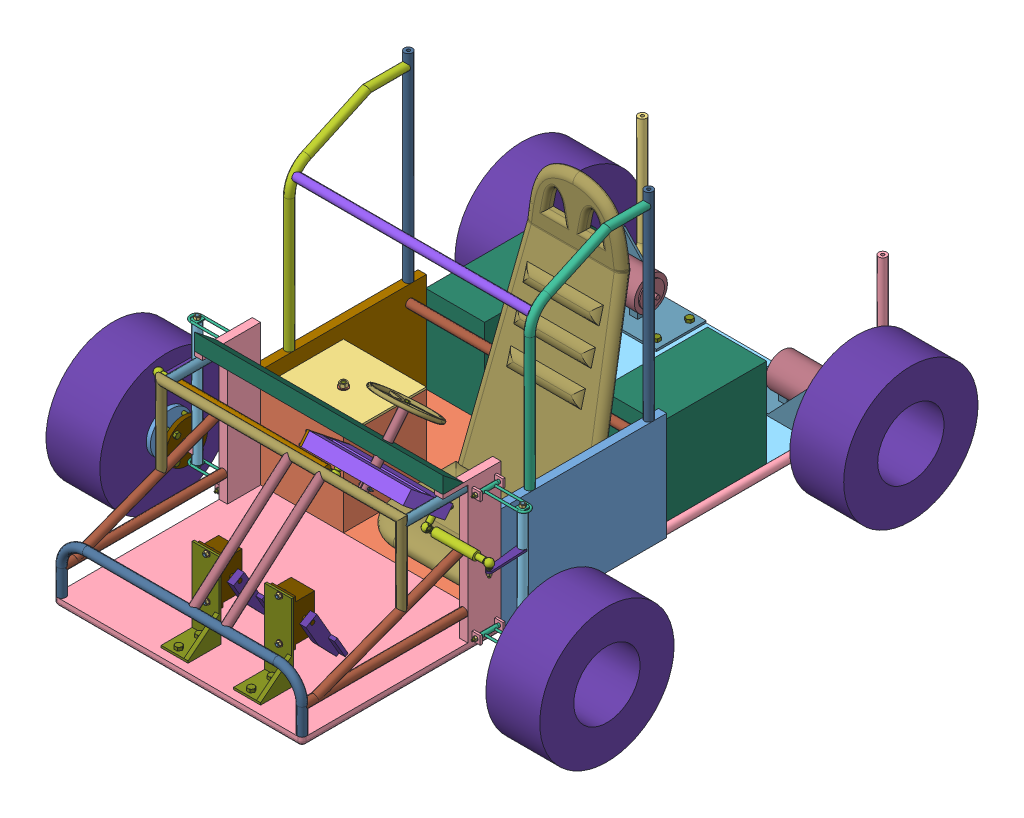
SolidWorks assembly FA2, configuration Default. Lengths in mm.
Overall size (1513.16 1181.12 1856.74).
253 component instances, 57 part files, 73 mates.
Components (placement in the parent):
- MC (1)-1: MC (1) [Default] at (-134.0082 207.4417 1496.2137) size (1191.26 1083.62 1343.85)
  - SPL-1: SPL [Default] at (646.5449 178.7927 -996.551) size (25.4 330.2 508)
  - BP-1: BP [Default] at (111.0665 -124.6065 -917.4807) size (711.2 25.4 508)
  - BBR-2: BBR [Default] at (-77.3551 -47.0728 -1647.3326) x (-1 0 0) z (0 -1 0) size (25.4 687.13 407.73)
  - BBL-1: BBL [Default] at (659.2449 -47.0728 -1647.3326) x (-1 0 0) z (0 -1 0) size (25.4 687.13 407.73)
  - BC-1: BC [Default] at (357.2961 -116.9228 -1647.3326) x (-1 0 0) z (0 0 -1) size (723.9 12.7 609.6)
  - FTL-1: FTL [Default] at (659.245 611.9935 -719.4116) x (0 -0.899323 -0.437285) z (-1 0 -0.000001) size (433.75 589.6 27.41)
  - FTR-1: FTR [Default] at (-77.355 611.9935 -719.4116) x (0 -0.899323 -0.437285) z (-1 0 -0.000001) size (433.75 589.6 27.38)
  - TC-1: TC [Default] at (652.8949 660.2535 -644.2461) x (0 -0.542655 -0.839955) z (-1 0 -0.000001) size (25.4 25.4 723.9)
  - SPR-1: SPR [Default] at (-90.0551 178.7927 -996.551) size (25.4 330.2 508)
  - BT-1: BT [Default] at (-77.3551 205.5935 -995.2506) x (0.000001 0 -1) z (1 0 0.000001) size (25.4 609.6 25.4)
  - BT-2: BT [Default] at (659.2449 205.5935 -995.2506) x (0.000001 0 -1) z (1 0 0.000001) size (25.4 609.6 25.4)
  - FB-1: FB [Default] at (-71.0051 154.7935 -986.9326) x (1 0 0) z (0 0.990518 0.137381) size (723.9 25.4 25.4)
  - seat-1: seat [Default] at (418.0013 -99.2065 -848.8249) size (437.03 835.23 478.09)
  - EA1-1: EA1 [Default] at (125.7912 -160.5315 -1631.3403) x (0 0 1) z (-1 0 0) size (411.48 411.48 1349.16)
    - EB1-1: EB1 [Default] at (60.2077 126.1588 196.7963) size (101.6 101.6 238.25)
    - EP1-1: EP1 [Default] at (60.2077 56.3088 69.7963) x (0 0 1) z (-1 0 0) size (254 133.35 152.4)
    - EA2-1: EA2 [Default] at (45.9187 58.6487 138.5565) size (411.48 411.48 213.36)
      - EP2-1: EP2 [Default] at (14.289 67.5101 114.1198) size (127 127 48.26)
      - hex bolt_ai-1: hex bolt_ai [HBOLT 0.4375-20x1.375x1.125-N] at (-36.511 67.5101 106.0934) x (0 0 1) z (-0.866025 -0.5 0) size (42.95 18.33 15.88)
      - hex bolt_ai-2: hex bolt_ai [HBOLT 0.4375-20x1.375x1.125-N] at (14.289 118.3101 106.0934) x (0 0 1) z (0 -1 0) size (42.95 18.33 15.88)
      - hex bolt_ai-3: hex bolt_ai [HBOLT 0.4375-20x1.375x1.125-N] at (14.289 16.7101 106.0934) x (0 0 1) z (-0.866025 0.5 0) size (42.95 18.33 15.88)
      - hex bolt_ai-4: hex bolt_ai [HBOLT 0.4375-20x1.375x1.125-N] at (65.089 67.5101 106.0934) x (0 0 1) z (-0.866025 0.5 0) size (42.95 18.33 15.88)
      - EB2-1: EB2 [Default] at (14.289 67.5101 129.9948) x (-1 0 0) z (0 0 -1) size (411.48 411.48 165.1)
      - flat washer type a wide_ai-1: flat washer type a wide_ai [Preferred Wide FW 0.4375] at (-36.511 67.5101 132.103) x (0 0 1) z (-0.923728 -0.383049 0) size (2.11 31.75 31.75)
      - flat washer type a wide_ai-2: flat washer type a wide_ai [Preferred Wide FW 0.4375] at (14.289 118.3101 132.103) x (0 0 1) z (1 0 0) size (2.11 31.75 31.75)
      - flat washer type a wide_ai-3: flat washer type a wide_ai [Preferred Wide FW 0.4375] at (14.289 16.7101 132.103) x (0 0 1) z (1 0 0) size (2.11 31.75 31.75)
      - flat washer type a wide_ai-4: flat washer type a wide_ai [Preferred Wide FW 0.4375] at (65.089 67.5101 132.103) x (0 0 1) z (1 0 0) size (2.11 31.75 31.75)
      - hex thick nut_ai-1: hex thick nut_ai [HTNUT 0.4375-14-D-N] at (14.289 16.7101 143.8632) x (0.055202 -0.998475 0) z (0 0 1) size (17.48 20.18 11.76)
      - hex thick nut_ai-2: hex thick nut_ai [HTNUT 0.4375-14-D-N] at (-36.511 67.5101 143.8632) x (0.547044 -0.837104 0) z (0 0 1) size (17.48 20.18 11.76)
      - hex thick nut_ai-3: hex thick nut_ai [HTNUT 0.4375-14-D-N] at (65.089 67.5101 143.8632) x (-0.982324 -0.18719 0) z (0 0 1) size (17.48 20.18 11.76)
      - hex thick nut_ai-4: hex thick nut_ai [HTNUT 0.4375-14-D-N] at (14.289 118.3101 143.8632) x (0.055202 -0.998475 0) z (0 0 1) size (17.48 20.18 11.76)
    - hex bolt_ai-8: hex bolt_ai [HBOLT 0.3125-18x1.375x0.875-N] at (17.0277 169.3388 215.4653) x (0 0 -1) z (0 1 0) size (40.89 14.66 12.7)
    - hex bolt_ai-9: hex bolt_ai [HBOLT 0.3125-18x1.375x0.875-N] at (103.3877 169.3388 215.4653) x (0 0 -1) z (0.866025 -0.5 0) size (40.89 14.66 12.7)
    - hex bolt_ai-10: hex bolt_ai [HBOLT 0.3125-18x1.375x0.875-N] at (103.3877 82.9788 215.4653) x (0 0 -1) z (0.866025 0.5 0) size (40.89 14.66 12.7)
    - hex bolt_ai-11: hex bolt_ai [HBOLT 0.3125-18x1.375x0.875-N] at (17.0277 82.9788 215.4653) x (0 0 -1) z (-0.866025 -0.5 0) size (40.89 14.66 12.7)
    - flat washer type a narrow_ai-1: flat washer type a narrow_ai [Preferred Narrow FW 0.3125] at (17.0277 169.3388 190.4463) x (0 0 1) z (-1 0 0) size (1.65 17.48 17.48)
    - flat washer type a narrow_ai-2: flat washer type a narrow_ai [Preferred Narrow FW 0.3125] at (103.3877 82.9788 190.4463) x (0 0 1) z (-1 0 0) size (1.65 17.48 17.48)
    - flat washer type a narrow_ai-3: flat washer type a narrow_ai [Preferred Narrow FW 0.3125] at (17.0277 82.9788 188.7953) x (0 0 -1) z (1 0 0) size (1.65 17.48 17.48)
    - flat washer type a narrow_ai-4: flat washer type a narrow_ai [Preferred Narrow FW 0.3125] at (103.3877 169.3388 188.7953) x (0 0 -1) z (0.923728 0.383049 0) size (1.65 17.48 17.48)
    - hex thick nut_ai-1: hex thick nut_ai [HTNUT 0.3125-18-D-N] at (103.3877 169.3388 188.7953) x (0.866025 0.5 0) z (0 0 1) size (12.7 14.66 8.53)
    - hex thick nut_ai-2: hex thick nut_ai [HTNUT 0.3125-18-D-N] at (17.0277 82.9788 180.2609) x (-0.866025 0.5 0) z (0 0 -1) size (12.7 14.66 8.53)
    - hex thick nut_ai-3: hex thick nut_ai [HTNUT 0.3125-18-D-N] at (103.3877 82.9788 181.9119) x (-0.866025 -0.5 0) z (0 0 -1) size (12.7 14.66 8.53)
    - hex thick nut_ai-4: hex thick nut_ai [HTNUT 0.3125-18-D-N] at (17.0277 169.3388 180.2609) x (-0.866025 -0.5 0) z (0 0 -1) size (12.7 14.66 8.53)
  - EA1-2: EA1 [Default] at (456.0986 -160.5315 -1510.9249) x (0 0 -1) z (1 0 0) size (411.48 411.48 1349.16)
    - EB1-1: EB1 [Default] at (60.2077 126.1588 196.7963) size (101.6 101.6 238.25)
    - EP1-1: EP1 [Default] at (60.2077 56.3088 69.7963) x (0 0 1) z (-1 0 0) size (254 133.35 152.4)
    - EA2-1: EA2 [Default] at (45.9187 58.6487 138.5565) size (411.48 411.48 213.36)
      - EP2-1: EP2 [Default] at (14.289 67.5101 114.1198) size (127 127 48.26)
      - hex bolt_ai-1: hex bolt_ai [HBOLT 0.4375-20x1.375x1.125-N] at (-36.511 67.5101 106.0934) x (0 0 1) z (-0.866025 -0.5 0) size (42.95 18.33 15.88)
      - hex bolt_ai-2: hex bolt_ai [HBOLT 0.4375-20x1.375x1.125-N] at (14.289 118.3101 106.0934) x (0 0 1) z (0 -1 0) size (42.95 18.33 15.88)
      - hex bolt_ai-3: hex bolt_ai [HBOLT 0.4375-20x1.375x1.125-N] at (14.289 16.7101 106.0934) x (0 0 1) z (-0.866025 0.5 0) size (42.95 18.33 15.88)
      - hex bolt_ai-4: hex bolt_ai [HBOLT 0.4375-20x1.375x1.125-N] at (65.089 67.5101 106.0934) x (0 0 1) z (-0.866025 0.5 0) size (42.95 18.33 15.88)
      - EB2-1: EB2 [Default] at (14.289 67.5101 129.9948) x (-1 0 0) z (0 0 -1) size (411.48 411.48 165.1)
      - flat washer type a wide_ai-1: flat washer type a wide_ai [Preferred Wide FW 0.4375] at (-36.511 67.5101 132.103) x (0 0 1) z (-0.923728 -0.383049 0) size (2.11 31.75 31.75)
      - flat washer type a wide_ai-2: flat washer type a wide_ai [Preferred Wide FW 0.4375] at (14.289 118.3101 132.103) x (0 0 1) z (1 0 0) size (2.11 31.75 31.75)
      - flat washer type a wide_ai-3: flat washer type a wide_ai [Preferred Wide FW 0.4375] at (14.289 16.7101 132.103) x (0 0 1) z (1 0 0) size (2.11 31.75 31.75)
      - flat washer type a wide_ai-4: flat washer type a wide_ai [Preferred Wide FW 0.4375] at (65.089 67.5101 132.103) x (0 0 1) z (1 0 0) size (2.11 31.75 31.75)
      - hex thick nut_ai-1: hex thick nut_ai [HTNUT 0.4375-14-D-N] at (14.289 16.7101 143.8632) x (0.055202 -0.998475 0) z (0 0 1) size (17.48 20.18 11.76)
      - hex thick nut_ai-2: hex thick nut_ai [HTNUT 0.4375-14-D-N] at (-36.511 67.5101 143.8632) x (0.547044 -0.837104 0) z (0 0 1) size (17.48 20.18 11.76)
      - hex thick nut_ai-3: hex thick nut_ai [HTNUT 0.4375-14-D-N] at (65.089 67.5101 143.8632) x (-0.982324 -0.18719 0) z (0 0 1) size (17.48 20.18 11.76)
      - hex thick nut_ai-4: hex thick nut_ai [HTNUT 0.4375-14-D-N] at (14.289 118.3101 143.8632) x (0.055202 -0.998475 0) z (0 0 1) size (17.48 20.18 11.76)
    - hex bolt_ai-8: hex bolt_ai [HBOLT 0.3125-18x1.375x0.875-N] at (17.0277 169.3388 215.4653) x (0 0 -1) z (0 1 0) size (40.89 14.66 12.7)
    - hex bolt_ai-9: hex bolt_ai [HBOLT 0.3125-18x1.375x0.875-N] at (103.3877 169.3388 215.4653) x (0 0 -1) z (0.866025 -0.5 0) size (40.89 14.66 12.7)
    - hex bolt_ai-10: hex bolt_ai [HBOLT 0.3125-18x1.375x0.875-N] at (103.3877 82.9788 215.4653) x (0 0 -1) z (0.866025 0.5 0) size (40.89 14.66 12.7)
    - hex bolt_ai-11: hex bolt_ai [HBOLT 0.3125-18x1.375x0.875-N] at (17.0277 82.9788 215.4653) x (0 0 -1) z (-0.866025 -0.5 0) size (40.89 14.66 12.7)
    - flat washer type a narrow_ai-1: flat washer type a narrow_ai [Preferred Narrow FW 0.3125] at (17.0277 169.3388 190.4463) x (0 0 1) z (-1 0 0) size (1.65 17.48 17.48)
    - flat washer type a narrow_ai-2: flat washer type a narrow_ai [Preferred Narrow FW 0.3125] at (103.3877 82.9788 190.4463) x (0 0 1) z (-1 0 0) size (1.65 17.48 17.48)
    - flat washer type a narrow_ai-3: flat washer type a narrow_ai [Preferred Narrow FW 0.3125] at (17.0277 82.9788 188.7953) x (0 0 -1) z (1 0 0) size (1.65 17.48 17.48)
    - flat washer type a narrow_ai-4: flat washer type a narrow_ai [Preferred Narrow FW 0.3125] at (103.3877 169.3388 188.7953) x (0 0 -1) z (0.923728 0.383049 0) size (1.65 17.48 17.48)
    - hex thick nut_ai-1: hex thick nut_ai [HTNUT 0.3125-18-D-N] at (103.3877 169.3388 188.7953) x (0.866025 0.5 0) z (0 0 1) size (12.7 14.66 8.53)
    - hex thick nut_ai-2: hex thick nut_ai [HTNUT 0.3125-18-D-N] at (17.0277 82.9788 180.2609) x (-0.866025 0.5 0) z (0 0 -1) size (12.7 14.66 8.53)
    - hex thick nut_ai-3: hex thick nut_ai [HTNUT 0.3125-18-D-N] at (103.3877 82.9788 181.9119) x (-0.866025 -0.5 0) z (0 0 -1) size (12.7 14.66 8.53)
    - hex thick nut_ai-4: hex thick nut_ai [HTNUT 0.3125-18-D-N] at (17.0277 169.3388 180.2609) x (-0.866025 -0.5 0) z (0 0 -1) size (12.7 14.66 8.53)
  - hex bolt_ai-1: hex bolt_ai [HBOLT 0.5000-13x1.375x1.25-N] at (157.5949 -88.6272 -1621.9326) x (0 -1 0) z (-1 0 0) size (44.17 22 19.05)
  - hex bolt_ai-2: hex bolt_ai [HBOLT 0.5000-13x1.375x1.25-N] at (157.5949 -88.6272 -1520.3326) x (0 -1 0) z (0.5 0 -0.866025) size (44.17 22 19.05)
  - hex bolt_ai-3: hex bolt_ai [HBOLT 0.5000-13x1.375x1.25-N] at (424.2949 -88.6272 -1520.3326) x (0 -1 0) z (1 0 0) size (44.17 22 19.05)
  - hex bolt_ai-4: hex bolt_ai [HBOLT 0.5000-13x1.375x1.25-N] at (602.0949 -88.6272 -1621.9326) x (0 -1 0) z (-0.5 0 -0.866025) size (44.17 22 19.05)
  - hex bolt_ai-5: hex bolt_ai [HBOLT 0.5000-13x1.375x1.25-N] at (424.2949 -88.6272 -1621.9326) x (0 -1 0) z (0.5 0 -0.866025) size (44.17 22 19.05)
  - hex bolt_ai-6: hex bolt_ai [HBOLT 0.5000-13x1.375x1.25-N] at (602.0949 -88.6272 -1520.3326) x (0 -1 0) z (-0.5 0 0.866025) size (44.17 22 19.05)
  - hex bolt_ai-7: hex bolt_ai [HBOLT 0.5000-13x1.375x1.25-N] at (-20.2051 -88.6272 -1621.9326) x (0 -1 0) z (-1 0 0) size (44.17 22 19.05)
  - hex bolt_ai-8: hex bolt_ai [HBOLT 0.5000-13x1.375x1.25-N] at (-20.2051 -88.6272 -1520.3326) x (0 -1 0) z (1 0 0) size (44.17 22 19.05)
  - flat washer type a wide_ai-1: flat washer type a wide_ai [Preferred Wide FW 0.5] at (157.5949 -119.6914 -1520.3326) x (0 -1 0) z (0.546944 0 -0.837169) size (2.77 34.92 34.92)
  - flat washer type a wide_ai-2: flat washer type a wide_ai [Preferred Wide FW 0.5] at (157.5949 -119.6914 -1621.9326) x (0 -1 0) z (0.967366 0 0.253384) size (2.77 34.92 34.92)
  - flat washer type a wide_ai-3: flat washer type a wide_ai [Preferred Wide FW 0.5] at (424.2949 -119.6914 -1621.9326) x (0 -1 0) z (-0.558017 0 -0.829829) size (2.77 34.92 34.92)
  - flat washer type a wide_ai-4: flat washer type a wide_ai [Preferred Wide FW 0.5] at (-20.2051 -119.6914 -1520.3326) x (0 -1 0) z (0.590888 0 -0.806754) size (2.77 34.92 34.92)
  - flat washer type a wide_ai-5: flat washer type a wide_ai [Preferred Wide FW 0.5] at (602.0949 -119.6914 -1520.3326) x (0 -1 0) z (0.610265 0 -0.792197) size (2.77 34.92 34.92)
  - flat washer type a wide_ai-6: flat washer type a wide_ai [Preferred Wide FW 0.5] at (424.2949 -119.6914 -1520.3326) x (0 -1 0) z (0.837672 0 -0.546174) size (2.77 34.92 34.92)
  - flat washer type a wide_ai-7: flat washer type a wide_ai [Preferred Wide FW 0.5] at (602.0949 -119.6914 -1621.9326) x (0 -1 0) z (0.97172 0 -0.236136) size (2.77 34.92 34.92)
  - flat washer type a wide_ai-8: flat washer type a wide_ai [Preferred Wide FW 0.5] at (-20.2051 -119.6914 -1621.9326) x (0 -1 0) z (0.345214 0 -0.938524) size (2.77 34.92 34.92)
  - hex nut_ai-1: hex nut_ai [HNUT 0.5000-13-D-N] at (157.5949 -131.0706 -1520.3326) x (-0.5 0 -0.866025) z (0 -1 0) size (19.05 22 11.38)
  - hex nut_ai-2: hex nut_ai [HNUT 0.5000-13-D-N] at (-20.2051 -131.0706 -1621.9326) x (-0.866025 0 -0.5) z (0 -1 0) size (19.05 22 11.38)
  - hex nut_ai-3: hex nut_ai [HNUT 0.5000-13-D-N] at (-20.2051 -131.0706 -1520.3326) x (0 0 -1) z (0 -1 0) size (19.05 22 11.38)
  - hex nut_ai-4: hex nut_ai [HNUT 0.5000-13-D-N] at (157.5949 -131.0706 -1621.9326) x (0 0 -1) z (0 -1 0) size (19.05 22 11.38)
  - hex nut_ai-5: hex nut_ai [HNUT 0.5000-13-D-N] at (424.2949 -131.0706 -1520.3326) x (0 0 1) z (0 -1 0) size (19.05 22 11.38)
  - hex nut_ai-6: hex nut_ai [HNUT 0.5000-13-D-N] at (424.2949 -131.0706 -1621.9326) x (-0.866025 0 0.5) z (0 -1 0) size (19.05 22 11.38)
  - hex nut_ai-8: hex nut_ai [HNUT 0.5000-13-D-N] at (602.0949 -131.0706 -1520.3326) x (-0.866025 0 -0.5) z (0 -1 0) size (19.05 22 11.38)
  - hex nut_ai-9: hex nut_ai [HNUT 0.5000-13-D-N] at (602.0949 -131.0706 -1621.9326) x (-0.866025 0 -0.5) z (0 -1 0) size (19.05 22 11.38)
  - hex bolt_ai-11: hex bolt_ai [HBOLT 0.5000-13x3x1.25-N] at (62.3449 -133.8521 -656.7326) x (0 1 0) z (-0.5 0 0.866025) size (85.45 22 19.05)
  - flat washer type a narrow_ai-1: flat washer type a narrow_ai [Preferred Narrow FW 0.5] at (62.3449 -99.2065 -656.7326) x (0 -1 0) z (0 0 1) size (2.41 26.97 26.97)
  - hex nut_ai-10: hex nut_ai [HNUT 0.5000-13-D-N] at (62.3449 -87.8273 -656.7326) x (1 0 0) z (0 1 0) size (19.05 22 11.38)
- FCA1-1: FCA1 [Default] at (-224.0632 159.0352 1576.0811) size (1513.16 852.83 849.49)
  - FCP1-1: FCP1 [Default] at origin size (812.8 457.2 609.6)
  - STA1-2: STA1 [Default] at (558.8 334.6162 -409.4012) x (-0.999987 0.003219 0.004024) z (0 0.780869 -0.624695) size (320.68 259.28 240.21)
    - STP10-3: STP10 [Default] at origin size (304.8 155.79 25.4)
      - spur gear_ai-4: spur gear_ai [Inch - Spur gear 6DP 25T 20PA 1FW ---S25N3.0H2.0L1.0S1] x (0 0 1) z (-0.989908 0.141715 0) size (25.4 113.98 114.2)
      - rack spur rectangular_ai-2: rack spur rectangular_ai [Inch - Rack-spur - rectangular 6DP 20PA 1FW 1.5PH 12L---SAll] at (-154.037 -91.44 25.4) size (304.8 42.33 25.4)
    - STP01-11: STP01 [Default] at (138.063 -75.0375 -39.3517) x (0 1 0) z (0 0 -1) size (23.88 20.07 47.75)
    - STP03-3: STP03 [Default] at (150.763 -97.79 31.75) x (0 0 -1) z (1 0 0) size (39.69 165.1 311.15)
    - STP04-3: STP04 [Default] at (150.763 -97.79 -7.9375) x (0 0 1) z (-1 0 0) size (39.69 165.1 6.59)
    - socket head cap screw_ai-1: socket head cap screw_ai [HX-SHCS 0.125-40x0.5x0.5-N] at (160.288 64.135 28.575) x (-1 0 0) z (0 0.866025 0.5) size (15.88 5.21 5.21)
    - socket head cap screw_ai-2: socket head cap screw_ai [HX-SHCS 0.125-40x0.5x0.5-N] at (160.288 64.135 -4.7625) x (-1 0 0) z (0 0.866025 0.5) size (15.88 5.21 5.21)
    - socket head cap screw_ai-4: socket head cap screw_ai [HX-SHCS 0.125-40x0.5x0.5-N] at (160.288 -94.615 28.575) x (-1 0 0) z (0 0.866025 0.5) size (15.88 5.21 5.21)
    - socket head cap screw_ai-7: socket head cap screw_ai [HX-SHCS 0.125-40x0.5x0.5-N] at (160.288 -94.615 -4.7625) x (-1 0 0) z (0 0.866025 0.5) size (15.88 5.21 5.21)
    - STP01-10: STP01 [Default] at (-141.337 -75.0375 -39.3517) x (0 -1 0) z (0 0 -1) size (23.88 20.07 47.75)
    - STP05-2: STP05 [Default] at (-154.037 -58.6317 0) x (1 0 0) z (0 0 -1) size (304.8 32.77 26.99)
    - STP06-1: STP06 [Default] at (-0.0036 -0.0251 180.975) x (0.5 -0.866025 0) z (0 0 1) size (189.81 189.81 12.01)
    - STP07-1: STP07 [Default] at (-0.0036 -0.0251 -33.528) x (-0.141715 -0.989908 0) z (0 0 1) size (28 24.77 211.33)
    - FWP4-1: FWP4 [Default] at (-20.7057 3.2593 -20.828) x (0 0 1) z (0.989908 -0.141715 0) size (12.7 12.7 39.95)
    - hex bolt_ai-1: hex bolt_ai [HBOLT 0.2500-20x0.75x0.75-N] at (-0.0036 -0.0251 188.9252) x (0 0 -1) z (0.5 0.866025 0) size (23.83 12.85 11.13)
  - STP08-1: STP08 [Default] at (469.9 381 -431.8) x (0 0 -1) z (1 0 0) size (63.5 50.8 762)
  - STP02-1: STP02 [Default] at (889.5958 256.5577 -445.8437) x (-0.961205 0 0.275836) z (0 1 0) size (16.51 16.51 46.05)
  - SP3-1: SP3 [Default] at (889.5958 238.8316 -445.8437) x (-0.086724 0 -0.996232) z (0 -1 0) size (120.39 25.32 6.35)
  - FWA1-1: FWA1 [Default] at (1025.989 75.5387 -589.4868) x (0 -0.682582 -0.730809) z (-1 0 0) size (411.48 411.48 257.81)
    - FWP5-2: FWP5 [Default] at (27.9791 75.0582 101.7677) size (127 127 48.26)
    - FWP1-1: FWP1 [Default] at (27.9791 75.0582 53.5077) size (127 127 48.26)
    - EB2-1: EB2 [Default] at (27.9791 75.0582 50.3327) x (-1 0 0) z (0 0 1) size (411.48 411.48 165.1)
    - internal tooth-lock washers_ai-1: internal tooth-lock washers_ai [Internal Tooth LW Type A-0.375] at (78.7791 75.0582 49.3167) x (0.992449 -0.122662 0) z (-0.122662 -0.992449 0) size (17.58 1.02 17.58)
    - internal tooth-lock washers_ai-2: internal tooth-lock washers_ai [Internal Tooth LW Type A-0.375] at (-22.8209 75.0582 49.3167) x (0.730809 -0.682582 0) z (-0.682582 -0.730809 0) size (17.58 1.02 17.58)
    - FWP2-2: FWP2 [Default] at (27.9791 75.0582 114.4677) x (-0.730809 0.682582 0) z (0 0 -1) size (9.53 9.53 14.29)
    - FWP3-2: FWP3 [Default] at (19.3103 65.7769 130.3427) x (0 0 1) z (-0.730809 0.682582 0) size (31.75 25.4 25.4)
    - FWP4-1: FWP4 [Default] at (13.8923 59.9761 123.9927) x (-0.730809 0.682582 0) z (0.682582 0.730809 0) size (12.7 12.7 39.95)
    - hex nut_ai-5: hex nut_ai [HNUT 0.4375-20-D-N] at (78.7791 75.0582 49.3167) x (0.291608 -0.956538 0) z (0 0 1) size (17.48 20.18 9.78)
    - internal tooth-lock washers_ai-5: internal tooth-lock washers_ai [Internal Tooth LW Type A-0.375] at (27.9791 24.2582 49.3167) x (-0.875007 -0.484111 0) z (-0.484111 0.875007 0) size (17.58 1.02 17.58)
    - internal tooth-lock washers_ai-6: internal tooth-lock washers_ai [Internal Tooth LW Type A-0.375] at (27.9791 125.8582 49.3167) x (0.730809 -0.682582 0) z (-0.682582 -0.730809 0) size (17.58 1.02 17.58)
    - hex nut_ai-7: hex nut_ai [HNUT 0.4375-20-D-N] at (-22.8209 75.0582 49.3167) x (0.291608 -0.956538 0) z (0 0 1) size (17.48 20.18 9.78)
    - hex nut_ai-8: hex nut_ai [HNUT 0.4375-20-D-N] at (27.9791 24.2582 39.5377) x (-0.97419 0.225729 0) z (0 0 -1) size (17.48 20.18 9.78)
    - hex nut_ai-9: hex nut_ai [HNUT 0.4375-20-D-N] at (27.9791 125.8582 49.3167) x (-0.97419 0.225729 0) z (0 0 1) size (17.48 20.18 9.78)
    - hex bolt_ai-1: hex bolt_ai [HBOLT 0.4375-20x3x1.125-N] at (78.7791 75.0582 122.4941) x (0 0 -1) z (-0.291608 0.956538 0) size (84.23 18.33 15.88)
    - hex bolt_ai-2: hex bolt_ai [HBOLT 0.4375-20x3x1.125-N] at (27.9791 125.8582 122.4941) x (0 0 -1) z (0.682582 0.730809 0) size (84.23 18.33 15.88)
    - hex bolt_ai-3: hex bolt_ai [HBOLT 0.4375-20x3x1.125-N] at (-22.8209 75.0582 122.4941) x (0 0 -1) z (0.97419 -0.225729 0) size (84.23 18.33 15.88)
    - hex bolt_ai-6: hex bolt_ai [HBOLT 0.4375-20x3x1.125-N] at (27.9791 24.2582 122.4941) x (0 0 -1) z (0.97419 -0.225729 0) size (84.23 18.33 15.88)
  - SA1-3: SA1 [Default] at (902.3249 84.601 -573.897) x (-0.581832 0 -0.813309) z (0 1 0) size (129.23 145.39 403.48)
    - SS1-1: SS1 [Default] at (0.7633 27.1847 256.5845) x (1 0 0) z (0 0 1) size (25.4 25.4 403.48)
    - SP2-2: SP2 [Default] at (87.3872 94.4048 258.172) x (0.581832 0.813309 0) z (-0.813309 0.581832 0) size (133.34 12.7 63.5)
    - SP2-3: SP2 [Default] at (87.3872 94.4048 -122.701) x (0.581832 0.813309 0) z (-0.813309 0.581832 0) size (133.34 12.7 63.5)
    - hex nut_ai-3: hex nut_ai [HNUT 0.3750-24-D-N] at (0.7633 27.1846 -132.8483) x (0.910536 0.41343 0) z (0 0 -1) size (14.27 16.48 8.56)
    - hex nut_ai-4: hex nut_ai [HNUT 0.3750-24-D-N] at (0.7633 27.1847 268.3193) x (0.910536 0.41343 0) z (0 0 1) size (14.27 16.48 8.56)
  - STP09-1: STP09 [Default] at (724.7148 240.1747 -456.9263) x (0.009813 0 0.999952) z (-0.999952 0 0.009813) size (25.4 25.4 152.4)
  - STP02-2: STP02 [Default] at (699.7485 256.5577 -443.9807) x (-0.004906 -0.866025 -0.499976) z (-0.999952 0 0.009813) size (16.51 16.51 46.05)
  - STP01-3: STP01 [Default] at (889.5958 256.5577 -445.8437) x (0.009813 0 0.999952) z (0.999952 0 -0.009813) size (23.88 20.07 47.75)
  - hex bolt_ai-1: hex bolt_ai [HBOLT 0.2500-20x3.5x0.75-N] at (774.7 342.9 -601.6752) x (0 0 1) z (-1 0 0) size (93.68 12.85 11.13)
  - external tooth lock washer_ai-1: external tooth lock washer_ai [ASME B18.21.1 - 0.256] at (774.7 342.9 -520.7) x (0 0 -1) z (0.999649 0.026486 0) size (0.58 12.4 12.55)
  - hex nut_ai-1: hex nut_ai [HNUT 0.2500-28-D-N] at (774.7 342.9 -514.3754) x (0.5 -0.866025 0) z (0 0 1) size (11.11 12.83 5.74)
  - hex bolt_ai-2: hex bolt_ai [HBOLT 0.2500-20x3.5x0.75-N] at (774.7 -38.1 -601.6752) x (0 0 1) z (-0.5 0.866025 0) size (93.68 12.85 11.13)
  - external tooth lock washer_ai-2: external tooth lock washer_ai [ASME B18.21.1 - 0.256] at (774.7 -38.1 -520.7) x (0 0 -1) z (0.643979 -0.765044 0) size (0.58 12.4 12.55)
  - hex nut_ai-2: hex nut_ai [HNUT 0.2500-28-D-N] at (774.7 -38.1 -514.3754) x (0.5 -0.866025 0) z (0 0 1) size (11.11 12.83 5.74)
  - FWA1-2: FWA1 [Default] at (-263.989 -72.2367 -589.4868) x (0 0.682582 -0.730809) z (1 0 0) size (411.48 411.48 257.81)
    - FWP5-2: FWP5 [Default] at (27.9791 75.0582 101.7677) size (127 127 48.26)
    - FWP1-1: FWP1 [Default] at (27.9791 75.0582 53.5077) size (127 127 48.26)
    - EB2-1: EB2 [Default] at (27.9791 75.0582 50.3327) x (-1 0 0) z (0 0 1) size (411.48 411.48 165.1)
    - internal tooth-lock washers_ai-1: internal tooth-lock washers_ai [Internal Tooth LW Type A-0.375] at (78.7791 75.0582 49.3167) x (0.992449 -0.122662 0) z (-0.122662 -0.992449 0) size (17.58 1.02 17.58)
    - internal tooth-lock washers_ai-2: internal tooth-lock washers_ai [Internal Tooth LW Type A-0.375] at (-22.8209 75.0582 49.3167) x (0.730809 -0.682582 0) z (-0.682582 -0.730809 0) size (17.58 1.02 17.58)
    - FWP2-2: FWP2 [Default] at (27.9791 75.0582 114.4677) x (-0.730809 0.682582 0) z (0 0 -1) size (9.53 9.53 14.29)
    - FWP3-2: FWP3 [Default] at (19.3103 65.7769 130.3427) x (0 0 1) z (-0.730809 0.682582 0) size (31.75 25.4 25.4)
    - FWP4-1: FWP4 [Default] at (13.8923 59.9761 123.9927) x (-0.730809 0.682582 0) z (0.682582 0.730809 0) size (12.7 12.7 39.95)
    - hex nut_ai-5: hex nut_ai [HNUT 0.4375-20-D-N] at (78.7791 75.0582 49.3167) x (0.291608 -0.956538 0) z (0 0 1) size (17.48 20.18 9.78)
    - internal tooth-lock washers_ai-5: internal tooth-lock washers_ai [Internal Tooth LW Type A-0.375] at (27.9791 24.2582 49.3167) x (-0.875007 -0.484111 0) z (-0.484111 0.875007 0) size (17.58 1.02 17.58)
    - internal tooth-lock washers_ai-6: internal tooth-lock washers_ai [Internal Tooth LW Type A-0.375] at (27.9791 125.8582 49.3167) x (0.730809 -0.682582 0) z (-0.682582 -0.730809 0) size (17.58 1.02 17.58)
    - hex nut_ai-7: hex nut_ai [HNUT 0.4375-20-D-N] at (-22.8209 75.0582 49.3167) x (0.291608 -0.956538 0) z (0 0 1) size (17.48 20.18 9.78)
    - hex nut_ai-8: hex nut_ai [HNUT 0.4375-20-D-N] at (27.9791 24.2582 39.5377) x (-0.97419 0.225729 0) z (0 0 -1) size (17.48 20.18 9.78)
    - hex nut_ai-9: hex nut_ai [HNUT 0.4375-20-D-N] at (27.9791 125.8582 49.3167) x (-0.97419 0.225729 0) z (0 0 1) size (17.48 20.18 9.78)
    - hex bolt_ai-1: hex bolt_ai [HBOLT 0.4375-20x3x1.125-N] at (78.7791 75.0582 122.4941) x (0 0 -1) z (-0.291608 0.956538 0) size (84.23 18.33 15.88)
    - hex bolt_ai-2: hex bolt_ai [HBOLT 0.4375-20x3x1.125-N] at (27.9791 125.8582 122.4941) x (0 0 -1) z (0.682582 0.730809 0) size (84.23 18.33 15.88)
    - hex bolt_ai-3: hex bolt_ai [HBOLT 0.4375-20x3x1.125-N] at (-22.8209 75.0582 122.4941) x (0 0 -1) z (0.97419 -0.225729 0) size (84.23 18.33 15.88)
    - hex bolt_ai-6: hex bolt_ai [HBOLT 0.4375-20x3x1.125-N] at (27.9791 24.2582 122.4941) x (0 0 -1) z (0.97419 -0.225729 0) size (84.23 18.33 15.88)
  - SA1-4: SA1 [Default] at (-140.3249 220.199 -573.897) x (0.581832 0 -0.813309) z (0 -1 0) size (129.23 145.39 403.48)
    - SS1-1: SS1 [Default] at (0.7633 27.1847 256.5845) x (1 0 0) z (0 0 1) size (25.4 25.4 403.48)
    - SP2-2: SP2 [Default] at (87.3872 94.4048 258.172) x (0.581832 0.813309 0) z (-0.813309 0.581832 0) size (133.34 12.7 63.5)
    - SP2-3: SP2 [Default] at (87.3872 94.4048 -122.701) x (0.581832 0.813309 0) z (-0.813309 0.581832 0) size (133.34 12.7 63.5)
    - hex nut_ai-3: hex nut_ai [HNUT 0.3750-24-D-N] at (0.7633 27.1846 -132.8483) x (0.910536 0.41343 0) z (0 0 -1) size (14.27 16.48 8.56)
    - hex nut_ai-4: hex nut_ai [HNUT 0.3750-24-D-N] at (0.7633 27.1847 268.3193) x (0.910536 0.41343 0) z (0 0 1) size (14.27 16.48 8.56)
  - hex bolt_ai-4: hex bolt_ai [HBOLT 0.2500-20x3.5x0.75-N] at (-12.7 342.9 -601.6752) x (0 0 1) z (-1 0 0) size (93.68 12.85 11.13)
  - external tooth lock washer_ai-9: external tooth lock washer_ai [ASME B18.21.1 - 0.256] at (-12.7 342.9 -520.7) x (0 0 -1) z (0.602564 -0.798071 0) size (0.58 12.4 12.55)
  - hex nut_ai-3: hex nut_ai [HNUT 0.2500-28-D-N] at (-12.7 342.9 -514.3754) size (11.11 12.83 5.74)
  - SP3-2: SP3 [Default] at (-123.1466 232.2195 -445.5445) x (0.047449 0 -0.998874) z (0 1 0) size (120.39 25.32 6.35)
  - hex nut_ai-4: hex nut_ai [HNUT 0.3125-24-D-N] at (889.5958 225.5474 -445.8437) x (0.986789 0 0.162012) z (0 -1 0) size (12.7 14.66 6.93)
  - STP010-1: STP010 [Default] at (395.2241 278.1416 -442.6472) x (-0.002815 -0.625306 0.780375) z (0.999986 0.00167 0.004946) size (25.4 25.4 508)
  - STP02-3: STP02 [Default] at (420.3522 257.4571 -442.8565) x (0.004395 -0.780378 -0.625293) z (0.999986 0.00167 0.004946) size (16.51 16.51 46.05)
  - STP02-4: STP02 [Default] at (-123.1466 256.5497 -445.5445) x (0.666341 0 0.745647) z (0 1 0) size (16.51 16.51 46.05)
  - hex nut_ai-5: hex nut_ai [HNUT 0.3125-24-D-N] at (-123.1466 225.2853 -445.5445) x (-0.977382 0 -0.211483) z (0 -1 0) size (12.7 14.66 6.93)
  - STP01-5: STP01 [Default] at (-123.1466 256.5497 -445.5445) x (0.005218 -0.342016 -0.93968) z (-0.999986 -0.00167 -0.004946) size (23.88 20.07 47.75)
  - hex bolt_ai-5: hex bolt_ai [HBOLT 0.2500-20x3.5x0.75-N] at (-12.7 -37.973 -601.6752) x (0 0 1) z (-1 0 0) size (93.68 12.85 11.13)
  - external tooth lock washer_ai-10: external tooth lock washer_ai [ASME B18.21.1 - 0.256] at (-12.7 -37.973 -520.7) x (0 0 -1) z (0.999649 -0.026486 0) size (0.58 12.4 12.55)
  - hex nut_ai-6: hex nut_ai [HNUT 0.2500-28-D-N] at (-12.7 -37.973 -520.1158) x (0.5 0.866025 0) z (0 0 -1) size (11.11 12.83 5.74)
  - FCP2-1: FCP2 [Default] at (12.7 -50.8 -12.7) size (762 168.4 25.4)
  - FCP3-1: FCP3 [Default] at (12.7 25.4 -508) x (0.992649 -0.121026 0) z (0 0 1) size (25.4 25.4 495.3)
  - FCP3-2: FCP3 [Default] at (749.3 25.4 -508) size (25.4 25.4 495.3)
  - FCP3-4: FCP3 [Default] at (12.7 25.4 -50.8) x (0.846332 0.498186 0.188503) z (0 0.353892 -0.935286) size (25.4 25.4 495.3)
  - FCP4-1: FCP4 [Default] at (12.7 127 -317.5) size (762 254 25.4)
  - FCP3-6: FCP3 [Default] at (749.3 200.6828 -514.0473) x (1 0 0) z (0 -0.353892 0.935286) size (25.4 25.4 495.3)
  - FCP5-1: FCP5 [Default] at (408.6538 104.14 -15.24) x (1 0 0) z (0 -0.658057 0.752969) size (25.4 25.4 401.32)
  - FCP5-2: FCP5 [Default] at (508 104.14 -15.24) x (1 0 0) z (0 -0.658057 0.752969) size (25.4 25.4 401.32)
  - FCP6-1: FCP6 [Default] at (749.3 355.6 -508) size (25.4 25.4 190.5)
  - FCP6-2: FCP6 [Default] at (12.7 355.6 -508) size (25.4 25.4 190.5)
- EB3-1: EB3 [Default] at (-201.2514 239.236 293.8891) x (0 0 -1) z (1 0 0) size (329.18 272.03 181.1)
- EB3-2: EB3 [Default] at (515.1249 239.236 293.8891) x (0 0 1) z (-1 0 0) size (329.18 272.03 181.1)
- EA4-1: EA4 [Default] at (112.4728 224.5389 1520.8381) x (-1 0 0) z (0 0 -1) size (143.05 262.66 260.65)
  - EB5-1: EB5 [Default] at (-114.2478 -116.3037 -29.843) size (82.55 234.95 101.6)
  - EA3-1: EA3 [Default] at (-6.3794 -155.1404 121.9178) x (-1 0 0) z (0 0.866025 -0.5) size (143.05 125.43 222.11)
    - EB4_2-1: EB4_2 [Default] at (50.3684 86.3483 116.5793) size (58.1 38.1 153)
    - EB4_1-1: EB4_1 [Default] at (-27.6316 86.3483 185.4593) x (0 0.5 0.866025) z (1 0 0) size (140 64 124)
  - t-head bolt_ai-1: t-head bolt_ai [TBOLT 0.3125-18x0.875x0.875-N] at (-14.7478 110.1463 84.107) x (0 0 -1) z (0 -1 0) size (28.57 15.67 7.94)
  - t-head bolt_ai-2: t-head bolt_ai [TBOLT 0.3125-18x0.875x0.875-N] at (-14.7478 -17.1037 84.107) x (0 0 -1) z (0 -1 0) size (28.57 15.67 7.94)
  - flat washer type a narrow_ai-1: flat washer type a narrow_ai [Preferred Narrow FW 0.3125] at (-14.7478 -17.1037 63.756) x (0 0 -1) z (0.923728 0.383049 0) size (1.65 17.48 17.48)
  - flat washer type a narrow_ai-2: flat washer type a narrow_ai [Preferred Narrow FW 0.3125] at (-14.7478 110.1463 63.756) x (0 0 -1) z (0.923728 0.383049 0) size (1.65 17.48 17.48)
  - hex nut_ai-1: hex nut_ai [HNUT 0.3125-18-D-N] at (-14.7478 110.1463 63.756) x (0.866025 -0.5 0) z (0 0 1) size (12.7 14.66 6.93)
  - hex nut_ai-2: hex nut_ai [HNUT 0.3125-18-D-N] at (-14.7478 -17.1037 63.756) x (0.866025 -0.5 0) z (0 0 1) size (12.7 14.66 6.93)
- EA4-2: EA4 [Default] at (334.7889 224.5389 1520.8381) x (-1 0 0) z (0 0 -1) size (143.05 262.66 260.65)
  - EB5-1: EB5 [Default] at (-114.2478 -116.3037 -29.843) size (82.55 234.95 101.6)
  - EA3-1: EA3 [Default] at (-6.3794 -155.1404 121.9178) x (-1 0 0) z (0 0.866025 -0.5) size (143.05 125.43 222.11)
    - EB4_2-1: EB4_2 [Default] at (50.3684 86.3483 116.5793) size (58.1 38.1 153)
    - EB4_1-1: EB4_1 [Default] at (-27.6316 86.3483 185.4593) x (0 0.5 0.866025) z (1 0 0) size (140 64 124)
  - t-head bolt_ai-1: t-head bolt_ai [TBOLT 0.3125-18x0.875x0.875-N] at (-14.7478 110.1463 84.107) x (0 0 -1) z (0 -1 0) size (28.57 15.67 7.94)
  - t-head bolt_ai-2: t-head bolt_ai [TBOLT 0.3125-18x0.875x0.875-N] at (-14.7478 -17.1037 84.107) x (0 0 -1) z (0 -1 0) size (28.57 15.67 7.94)
  - flat washer type a narrow_ai-1: flat washer type a narrow_ai [Preferred Narrow FW 0.3125] at (-14.7478 -17.1037 63.756) x (0 0 -1) z (0.923728 0.383049 0) size (1.65 17.48 17.48)
  - flat washer type a narrow_ai-2: flat washer type a narrow_ai [Preferred Narrow FW 0.3125] at (-14.7478 110.1463 63.756) x (0 0 -1) z (0.923728 0.383049 0) size (1.65 17.48 17.48)
  - hex nut_ai-1: hex nut_ai [HNUT 0.3125-18-D-N] at (-14.7478 110.1463 63.756) x (0.866025 -0.5 0) z (0 0 1) size (12.7 14.66 6.93)
  - hex nut_ai-2: hex nut_ai [HNUT 0.3125-18-D-N] at (-14.7478 -17.1037 63.756) x (0.866025 -0.5 0) z (0 0 1) size (12.7 14.66 6.93)
- hex bolt_ai-1: hex bolt_ai [HBOLT 0.5000-13x1.875x1.25-N] at (115.5956 123.8308 1531.6311) x (0 -1 0) z (0 0 1) size (56.87 22 19.05)
- hex bolt_ai-2: hex bolt_ai [HBOLT 0.5000-13x1.875x1.25-N] at (337.9118 123.8308 1531.6311) x (0 -1 0) z (0 0 1) size (56.87 22 19.05)
- hex bolt_ai-3: hex bolt_ai [HBOLT 0.5000-13x1.875x1.25-N] at (337.9118 123.8308 1468.1311) x (0 -1 0) z (-0.866025 0 -0.5) size (56.87 22 19.05)
- hex bolt_ai-4: hex bolt_ai [HBOLT 0.5000-13x1.875x1.25-N] at (115.5956 123.8308 1468.1311) x (0 -1 0) z (0 0 1) size (56.87 22 19.05)
- flat washer type a narrow_ai-1: flat washer type a narrow_ai [Preferred Narrow FW 0.5] at (337.9118 82.8352 1468.1311) x (0 1 0) z (0.940911 0 0.338655) size (2.41 26.97 26.97)
- flat washer type a narrow_ai-2: flat washer type a narrow_ai [Preferred Narrow FW 0.5] at (337.9118 80.4222 1531.6311) x (0 -1 0) z (0.5 0 0.866025) size (2.41 26.97 26.97)
- flat washer type a narrow_ai-3: flat washer type a narrow_ai [Preferred Narrow FW 0.5] at (115.5956 80.4222 1531.6311) x (0 -1 0) z (-0.546944 0 0.837169) size (2.41 26.97 26.97)
- flat washer type a narrow_ai-4: flat washer type a narrow_ai [Preferred Narrow FW 0.5] at (115.5956 80.4222 1468.1311) x (0 -1 0) z (-0.546944 0 0.837169) size (2.41 26.97 26.97)
- hex nut_ai-1: hex nut_ai [HNUT 0.5000-13-D-N] at (115.5956 80.4222 1468.1311) x (0 0 -1) z (0 1 0) size (19.05 22 11.38)
- hex nut_ai-2: hex nut_ai [HNUT 0.5000-13-D-N] at (337.9118 69.043 1468.1311) x (0.866025 0 0.5) z (0 -1 0) size (19.05 22 11.38)
- hex nut_ai-3: hex nut_ai [HNUT 0.5000-13-D-N] at (337.9118 69.043 1531.6311) x (0.866025 0 -0.5) z (0 -1 0) size (19.05 22 11.38)
- hex nut_ai-4: hex nut_ai [HNUT 0.5000-13-D-N] at (115.5956 69.043 1531.6311) x (0.866025 0 0.5) z (0 -1 0) size (19.05 22 11.38)
- hex bolt_ai-8: hex bolt_ai [HBOLT 0.5000-13x3x1.25-N] at (375.9255 154.0462 784.0565) x (0 -1 0) z (0 0 1) size (85.45 22 19.05)
- hex bolt_ai-9: hex bolt_ai [HBOLT 0.5000-13x3x1.25-N] at (192.0608 154.0462 784.0565) x (0 -1 0) z (-0.866025 0 0.5) size (85.45 22 19.05)
- flat washer type a narrow_ai-5: flat washer type a narrow_ai [Preferred Narrow FW 0.5] at (192.0608 80.4222 784.0565) x (0 -1 0) z (-0.88596 0 0.463763) size (2.41 26.97 26.97)
- flat washer type a narrow_ai-6: flat washer type a narrow_ai [Preferred Narrow FW 0.5] at (375.9255 80.4222 784.0565) x (0 -1 0) z (-0.025683 0 0.99967) size (2.41 26.97 26.97)
- hex nut_ai-5: hex nut_ai [HNUT 0.5000-13-D-N] at (375.9255 71.456 784.0565) x (1 0 0) z (0 -1 0) size (19.05 22 11.38)
- hex nut_ai-6: hex nut_ai [HNUT 0.5000-13-D-N] at (192.0608 71.456 784.0565) x (1 0 0) z (0 -1 0) size (19.05 22 11.38)
- EA5-1: EA5 [Default] at (-4.6103 125.1358 543.8474) size (254 872.68 254)
  - EP3-1: EP3 [Default] at (-67.0529 -16.9006 295.6337) size (254 254 254)
  - EP4-1: EP4 [Default] at (-67.0529 237.0994 295.6337) x (0 0 1) z (-1 0 0) size (254 6.35 254)
  - hex bolt_ai-1: hex bolt_ai [HBOLT 0.5000-13x1x1-N] at (-67.0529 221.5038 295.6337) x (0 1 0) z (0 0 1) size (34.65 22 19.05)
  - flat washer type a narrow_ai-1: flat washer type a narrow_ai [Preferred Narrow FW 0.5] at (-67.0529 245.8624 295.6337) x (0 1 0) z (-0.546944 0 0.837169) size (2.41 26.97 26.97)
  - hex nut_ai-3: hex nut_ai [HNUT 0.5000-13-D-N] at (-67.0529 257.2416 295.6337) x (1 0 0) z (0 1 0) size (19.05 22 11.38)
Mates (geometry in assembly coordinates):
- Coincident1: coincident: plane of MC (1)-1/BP-1 through (-198.6632 108.2352 966.4811) normal (0 0 1); plane of FCA1-1/FCP1-1 through (-224.0632 159.0352 966.4811) normal (0 0 -1)
- Coincident2: coincident: plane of MC (1)-1/SPL-1 through (537.9368 413.0352 966.4811) normal (0 0 1); plane of FCA1-1/FCP1-1 through (-224.0632 159.0352 966.4811) normal (0 0 -1)
- Coincident3: coincident: plane of MC (1)-1/SPL-1 through (537.9368 413.0352 966.4811) normal (0 0 1); plane of FCA1-1/FCP1-1 through (-224.0632 159.0352 966.4811) normal (0 0 -1)
- Coincident4: coincident: line of MC (1)-1/SPR-1 through (-224.0632 413.0352 966.4811) axis (0 -1 0); line of FCA1-1/FCP1-1 through (-224.0632 540.0352 966.4811) axis (0 -1 0)
- Coincident6: coincident: line of MC (1)-1/BP-1 through (-198.6632 82.8352 966.4811) axis (1 0 0); line of FCA1-1/FCP1-1 through (525.2368 82.8352 966.4811) axis (-1 0 0)
- Coincident7: coincident: plane of MC (1)-1/BC-1 through (223.2879 103.219 -151.1189) normal (0 1 0); plane of EB3-1 through (-20.1494 103.219 458.4811) normal (0 -1 0)
- Coincident8: coincident: line of MC (1)-1/BBR-2 through (-201.2514 103.219 458.4811) axis (0 0 -1); line of EB3-1 through (-201.2514 103.219 458.4811) axis (0 0 -1)
- Parallel3: parallel: line of MC (1)-1/SPR-1 through (-198.6632 82.8352 458.4811) axis (0 1 0); line of EB3-1 through (-201.2514 375.253 458.4811) axis (0 -1 0)
- Coincident13: coincident: plane of MC (1)-1/BP-1 through (-198.6632 108.2352 458.4811) normal (0 0 -1); plane of EB3-1 through (-20.1494 375.253 458.4811) normal (0 0 1)
- Coincident14: coincident: plane of MC (1)-1/BC-1 through (223.2879 103.219 -151.1189) normal (0 1 0); plane of EB3-2 through (334.0229 103.219 129.2971) normal (0 -1 0)
- Coincident15: coincident: line of MC (1)-1/BBL-1 through (515.1249 103.219 -151.1189) axis (0 0 1); line of EB3-2 through (515.1249 103.219 129.2971) axis (0 0 1)
- Coincident16: coincident: plane of MC (1)-1/BP-1 through (-198.6632 108.2352 458.4811) normal (0 0 -1); plane of EB3-2 through (334.0229 375.253 458.4811) normal (0 0 1)
- Coincident17: coincident: plane of FCA1-1/FCP1-1 through (-224.0632 108.2352 1550.6811) normal (0 1 0); plane of EA4-1/EB5-1 through (80.6706 108.2352 1550.6811) normal (0 -1 0)
- Parallel4: parallel: line of MC (1)-1/BP-1 through (-198.6632 108.2352 966.4811) axis (1 0 0); line of EA4-1/EB5-1 through (80.6706 108.2352 1449.0811) axis (1 0 0)
- Distance2: distance = 482.6 mm: line of EA4-1/EB5-1 through (80.6706 108.2352 1449.0811) axis (1 0 0); line of FCA1-1/FCP1-1 through (512.5368 108.2352 966.4811) axis (-1 0 0)
- Parallel5: parallel: line of FCA1-1/FCP1-1 through (537.9368 108.2352 1563.3811) axis (0 0 -1); line of EA4-1/EB5-1 through (163.2206 108.2352 1550.6811) axis (0 0 -1)
- Distance3: distance = 304.8 mm: line of EA4-1/EB5-1 through (80.6706 114.5852 1550.6811) axis (0 0 -1); line of FCA1-1/FCP1-1 through (-224.0632 108.2352 1563.3811) axis (0 0 -1)
- Coincident22: coincident: plane of FCA1-1/FCP1-1 through (-224.0632 108.2352 1550.6811) normal (0 1 0); plane of EA4-2/EB5-1 through (302.9868 108.2352 1550.6811) normal (0 -1 0)
- Parallel6: parallel: line of FCA1-1/FCP1-1 through (512.5368 108.2352 966.4811) axis (-1 0 0); line of EA4-2/EB5-1 through (302.9868 108.2352 1449.0811) axis (1 0 0)
- Parallel7: parallel: line of FCA1-1/FCP1-1 through (537.9368 108.2352 1563.3811) axis (0 0 -1); line of EA4-2/EB5-1 through (385.5368 108.2352 1550.6811) axis (0 0 -1)
- Distance4: distance = 482.6 mm: line of FCA1-1/FCP1-1 through (512.5368 108.2352 966.4811) axis (-1 0 0); line of EA4-2/EB5-1 through (302.9868 108.2352 1449.0811) axis (1 0 0)
- Distance5: distance = 152.4 mm: line of EA4-2/EB5-1 through (385.5368 108.2352 1550.6811) axis (0 0 -1); line of FCA1-1/FCP1-1 through (537.9368 108.2352 1563.3811) axis (0 0 -1)
- Concentric1: concentric: cylinder of EA4-2/EB5-1 through (337.9118 101.8852 1468.1311) axis (0 1 0) radius 6.35; cylinder of hex bolt_ai-3 through (337.9118 123.8308 1468.1311) axis (0 1 0) radius 6.35
- Coincident27: coincident: plane of EA4-2/EB5-1 through (302.9868 114.5852 1550.6811) normal (0 1 0); plane of hex bolt_ai-3 through (332.4125 114.5852 1477.6561) normal (0 -1 0)
- Parallel8: parallel: plane of FCA1-1/FCP1-1 through (-224.0632 159.0352 1576.0811) normal (0 0 1); plane of hex bolt_ai-3 through (343.411 114.5852 1477.6561) normal (0 0 1)
- Concentric2: concentric: cylinder of hex bolt_ai-3 through (337.9118 123.8308 1468.1311) axis (0 1 0) radius 6.35; cylinder of flat washer type a narrow_ai-1 through (337.9118 47.9102 1468.1311) axis (0 -1 0) radius 6.7437
- Coincident29: coincident: plane of FCA1-1/FCP1-1 through (-224.0632 82.8352 2341.8816) normal (0 -1 0); plane of flat washer type a narrow_ai-1 through (335.628 82.8352 1474.4763) normal (0 1 0)
- Concentric4: concentric: cylinder of hex bolt_ai-3 through (337.9118 123.8308 1468.1311) axis (0 1 0) radius 6.35; cylinder of hex nut_ai-2 through (337.9118 80.4222 1468.1311) axis (0 -1 0) radius 5.3581
- Coincident31: coincident: plane of flat washer type a narrow_ai-1 through (333.3442 80.4222 1480.8215) normal (0 -1 0); plane of hex nut_ai-2 through (332.4125 80.4222 1477.6561) normal (0 1 0)
- Parallel9: parallel: line of FCA1-1/FCP1-1 through (525.2368 82.8352 1563.3811) axis (-1 0 0); plane of hex nut_ai-2 through (343.411 80.4222 1477.6561) normal (0 0 1)
- Concentric5: concentric: cylinder of FCA1-1/FCP1-1 through (337.9118 -130.1684 1531.6311) axis (0 1 0) radius 6.35; cylinder of hex bolt_ai-2 through (337.9118 123.8308 1531.6311) axis (0 1 0) radius 6.35
- Coincident33: coincident: plane of EA4-2/EB5-1 through (302.9868 114.5852 1550.6811) normal (0 1 0); plane of hex bolt_ai-2 through (348.9103 114.5852 1531.6311) normal (0 -1 0)
- Parallel10: parallel: plane of FCA1-1/FCP1-1 through (-224.0632 159.0352 1576.0811) normal (0 0 1); plane of hex bolt_ai-2 through (343.411 114.5852 1541.1561) normal (0 0 1)
- Concentric6: concentric: cylinder of hex bolt_ai-2 through (337.9118 123.8308 1531.6311) axis (0 1 0) radius 6.35; cylinder of flat washer type a narrow_ai-2 through (337.9118 115.3472 1531.6311) axis (0 1 0) radius 6.7437
- Coincident35: coincident: plane of FCA1-1/FCP1-1 through (-224.0632 82.8352 2341.8816) normal (0 -1 0); plane of flat washer type a narrow_ai-2 through (349.5922 82.8352 1524.8874) normal (0 1 0)
- Concentric7: concentric: cylinder of hex bolt_ai-2 through (337.9118 123.8308 1531.6311) axis (0 1 0) radius 6.35; cylinder of hex nut_ai-3 through (337.9118 80.4222 1531.6311) axis (0 -1 0) radius 5.3581
- Coincident36: coincident: plane of flat washer type a narrow_ai-2 through (343.752 80.4222 1528.2593) normal (0 -1 0); plane of hex nut_ai-3 through (343.411 80.4222 1541.1561) normal (0 1 0)
- Parallel11: parallel: plane of FCA1-1/FCP1-1 through (-224.0632 159.0352 1576.0811) normal (0 0 1); plane of hex nut_ai-3 through (343.411 80.4222 1541.1561) normal (0 0 1)
- Concentric8: concentric: cylinder of FCA1-1/FCP1-1 through (115.5956 -130.1684 1531.6311) axis (0 1 0) radius 6.35; cylinder of hex bolt_ai-1 through (115.5956 123.8308 1531.6311) axis (0 1 0) radius 6.35
- Coincident38: coincident: plane of EA4-1/EB5-1 through (80.6706 114.5852 1550.6811) normal (0 1 0); plane of hex bolt_ai-1 through (126.5941 114.5852 1531.6311) normal (0 -1 0)
- Parallel12: parallel: plane of FCA1-1/FCP1-1 through (-224.0632 159.0352 1576.0811) normal (0 0 1); plane of hex bolt_ai-1 through (121.0949 114.5852 1541.1561) normal (0 0 1)
- Concentric9: concentric: cylinder of hex bolt_ai-1 through (115.5956 123.8308 1531.6311) axis (0 1 0) radius 6.35; cylinder of flat washer type a narrow_ai-3 through (115.5956 115.3472 1531.6311) axis (0 1 0) radius 6.7437
- Coincident40: coincident: plane of FCA1-1/FCP1-1 through (-224.0632 82.8352 2341.8816) normal (0 -1 0); plane of flat washer type a narrow_ai-3 through (126.8869 82.8352 1539.008) normal (0 1 0)
- Concentric10: concentric: cylinder of hex bolt_ai-1 through (115.5956 123.8308 1531.6311) axis (0 1 0) radius 6.35; cylinder of hex nut_ai-4 through (115.5956 80.4222 1531.6311) axis (0 -1 0) radius 5.3581
- Coincident41: coincident: plane of flat washer type a narrow_ai-3 through (121.2412 80.4222 1535.3195) normal (0 -1 0); plane of hex nut_ai-4 through (110.0964 80.4222 1541.1561) normal (0 1 0)
- Parallel13: parallel: plane of FCA1-1/FCP1-1 through (-224.0632 159.0352 1576.0811) normal (0 0 1); plane of hex nut_ai-4 through (121.0949 80.4222 1541.1561) normal (0 0 1)
- Concentric11: concentric: cylinder of FCA1-1/FCP1-1 through (115.5956 -130.1684 1468.1311) axis (0 1 0) radius 6.35; cylinder of hex bolt_ai-4 through (115.5956 123.8308 1468.1311) axis (0 1 0) radius 6.35
- Coincident43: coincident: plane of EA4-1/EB5-1 through (80.6706 114.5852 1550.6811) normal (0 1 0); plane of hex bolt_ai-4 through (126.5941 114.5852 1468.1311) normal (0 -1 0)
- Parallel14: parallel: plane of FCA1-1/FCP1-1 through (-224.0632 159.0352 1576.0811) normal (0 0 1); plane of hex bolt_ai-4 through (121.0949 114.5852 1477.6561) normal (0 0 1)
- Concentric12: concentric: cylinder of hex bolt_ai-4 through (115.5956 123.8308 1468.1311) axis (0 1 0) radius 6.35; cylinder of flat washer type a narrow_ai-4 through (115.5956 115.3472 1468.1311) axis (0 1 0) radius 6.7437
- Coincident45: coincident: plane of FCA1-1/FCP1-1 through (-224.0632 82.8352 2341.8816) normal (0 -1 0); plane of flat washer type a narrow_ai-4 through (126.8869 82.8352 1475.508) normal (0 1 0)
- Concentric13: concentric: cylinder of hex bolt_ai-4 through (115.5956 123.8308 1468.1311) axis (0 1 0) radius 6.35; cylinder of hex nut_ai-1 through (115.5956 69.043 1468.1311) axis (0 1 0) radius 5.3581
- Coincident46: coincident: plane of flat washer type a narrow_ai-4 through (121.2412 80.4222 1471.8195) normal (0 -1 0); plane of hex nut_ai-1 through (104.5971 80.4222 1468.1311) normal (0 1 0)
- Parallel15: parallel: plane of FCA1-1/FCP1-1 through (-224.0632 159.0352 1576.0811) normal (0 0 1); plane of hex nut_ai-1 through (110.0964 69.043 1477.6561) normal (0 0 1)
- Concentric14: concentric: cylinder of MC (1)-1/seat-1 through (192.0608 -130.1684 784.0565) axis (0 1 0) radius 6.35; cylinder of hex bolt_ai-9 through (192.0608 154.0462 784.0565) axis (0 1 0) radius 6.35
- Concentric15: concentric: cylinder of MC (1)-1/seat-1 through (375.9255 -130.1684 784.0565) axis (0 1 0) radius 6.35; cylinder of hex bolt_ai-8 through (375.9255 154.0462 784.0565) axis (0 1 0) radius 6.35
- Coincident53: coincident: plane of MC (1)-1/seat-1 through (375.9255 144.8006 784.0565) normal (0 1 0); plane of hex bolt_ai-8 through (386.9241 144.8006 784.0565) normal (0 -1 0)
- Coincident54: coincident: plane of MC (1)-1/seat-1 through (192.0608 144.8006 784.0565) normal (0 1 0); plane of hex bolt_ai-9 through (197.56 144.8006 793.5815) normal (0 -1 0)
- Parallel18: parallel: line of MC (1)-1/seat-1 through (181.7442 154.9606 840.9212) axis (1 0 0); plane of hex bolt_ai-9 through (197.56 144.8006 793.5815) normal (0 0 1)
- Parallel19: parallel: line of MC (1)-1/seat-1 through (181.7442 154.9606 840.9212) axis (1 0 0); plane of hex bolt_ai-8 through (381.4248 144.8006 793.5815) normal (0 0 1)
- Concentric16: concentric: cylinder of hex bolt_ai-8 through (375.9255 154.0462 784.0565) axis (0 1 0) radius 6.35; cylinder of flat washer type a narrow_ai-6 through (375.9255 115.3472 784.0565) axis (0 1 0) radius 6.7437
- Concentric17: concentric: cylinder of hex bolt_ai-9 through (192.0608 154.0462 784.0565) axis (0 1 0) radius 6.35; cylinder of flat washer type a narrow_ai-5 through (192.0608 115.3472 784.0565) axis (0 1 0) radius 6.7437
- Coincident57: coincident: plane of MC (1)-1/BP-1 through (-22.9417 82.8352 578.733) normal (0 -1 0); plane of flat washer type a narrow_ai-6 through (389.4085 82.8352 784.4029) normal (0 1 0)
- Coincident58: coincident: plane of MC (1)-1/BP-1 through (-22.9417 82.8352 578.733) normal (0 -1 0); plane of flat washer type a narrow_ai-5 through (198.3157 82.8352 796.0058) normal (0 1 0)
- Coincident60: coincident: plane of MC (1)-1/BP-1 through (-22.9417 82.8352 578.733) normal (0 -1 0); plane of hex nut_ai-5 through (375.9255 82.8352 795.055) normal (0 1 0)
- Concentric19: concentric: cylinder of hex bolt_ai-9 through (192.0608 154.0462 784.0565) axis (0 1 0) radius 6.35; cylinder of hex nut_ai-6 through (192.0608 96.4935 784.0565) axis (0 -1 0) radius 6.35
- Coincident61: coincident: plane of MC (1)-1/BP-1 through (-22.9417 82.8352 578.733) normal (0 -1 0); plane of hex nut_ai-6 through (192.0608 82.8352 795.055) normal (0 1 0)
- Concentric20: concentric: cylinder of hex bolt_ai-8 through (375.9255 154.0462 784.0565) axis (0 1 0) radius 6.35; cylinder of hex nut_ai-5 through (375.9255 82.8352 784.0565) axis (0 -1 0) radius 5.3581
- Parallel20: parallel: plane of MC (1)-1/SPL-1 through (537.9368 386.2345 499.6627) normal (1 0 0); plane of hex nut_ai-5 through (385.4505 82.8352 789.5557) normal (1 0 0)
- Parallel21: parallel: plane of MC (1)-1/SPL-1 through (537.9368 386.2345 499.6627) normal (1 0 0); plane of hex nut_ai-6 through (201.5858 82.8352 789.5557) normal (1 0 0)
- Coincident62: coincident: plane of MC (1)-1/BP-1 through (-22.9417 108.2352 578.733) normal (0 1 0); plane of EA5-1/EP3-1 through (-71.6632 108.2352 839.4811) normal (0 -1 0)
- Coincident63: coincident: plane of MC (1)-1/SPR-1 through (-198.6632 386.2345 499.6627) normal (1 0 0); plane of EA5-1/EP3-1 through (-198.6632 362.2352 712.4811) normal (-1 0 0)
- Coincident64: coincident: line of MC (1)-1/BP-1 through (-198.6632 108.2352 966.4811) axis (1 0 0); line of EA5-1/EP3-1 through (-198.6632 108.2352 966.4811) axis (1 0 0)
